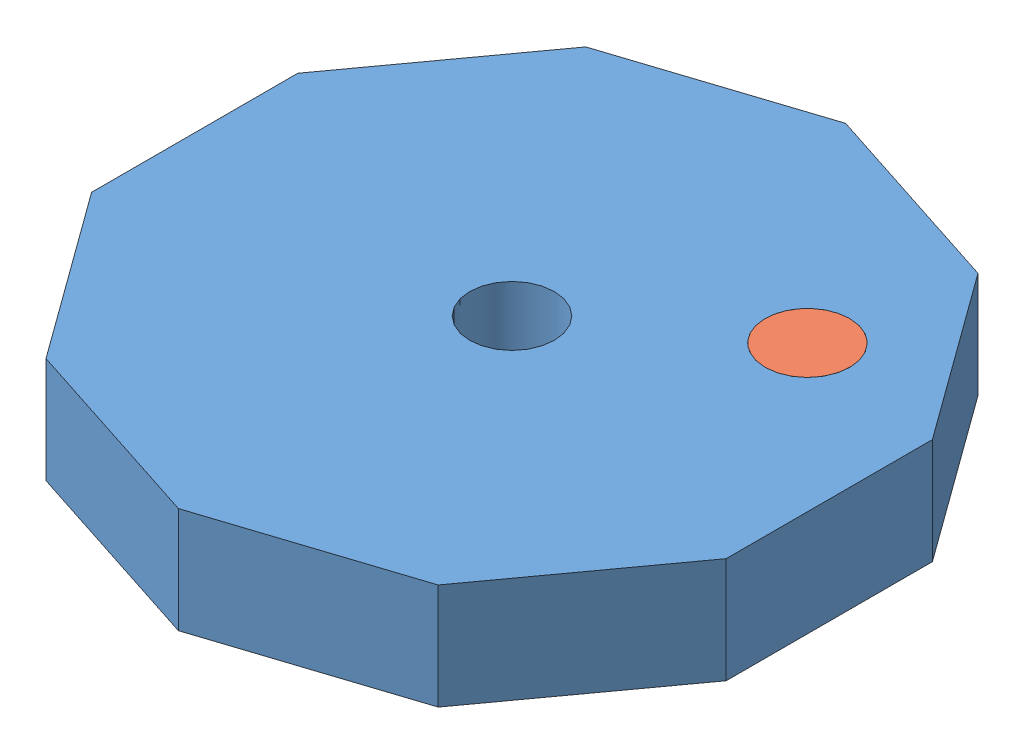
SolidWorks assembly Bottom with Conductive, configuration Default. Lengths in mm.
Overall size (31.57 5 31.54).
2 component instances, 2 part files, 5 mates.
Components (placement in the parent):
- Roatating Bottom-1: Roatating Bottom [Default] at (5.7148 9.9417 16.2713) size (30 5 31.54)
- Conductive 2-1: Conductive 2 [Default] at (5.7148 9.9417 16.2713) x (0.188203 0 -0.98213) z (0.98213 0 0.188203) size (13.94 5 15.43)
Mates (geometry in assembly coordinates):
- Coincident19: coincident: circle of Roatating Bottom-1; circle of Conductive Part-5
- Concentric15: concentric: circle of Roatating Bottom-1; circle of Conductive Part-5
- Concentric16: concentric: cylinder of Roatating Bottom-1 through (13.8049 12.9417 10.3935) axis (0 1 0) radius 2; cylinder of Conductive 2-1 through (13.8049 14.9417 10.3935) axis (0 -1 0) radius 2
- Concentric17: concentric: cylinder of Roatating Bottom-1 through (9.5344 12.9417 4.5156) axis (0 -1 0) radius 2; cylinder of Conductive 2-1 through (9.5344 12.9417 4.5156) axis (0 -1 0) radius 2
- Coincident20: coincident aligned: plane of Roatating Bottom-1 through (5.7148 9.9417 16.2713) normal (0 -1 0); plane of Conductive 2-1 through (5.7148 9.9417 16.2713) normal (0 -1 0)
